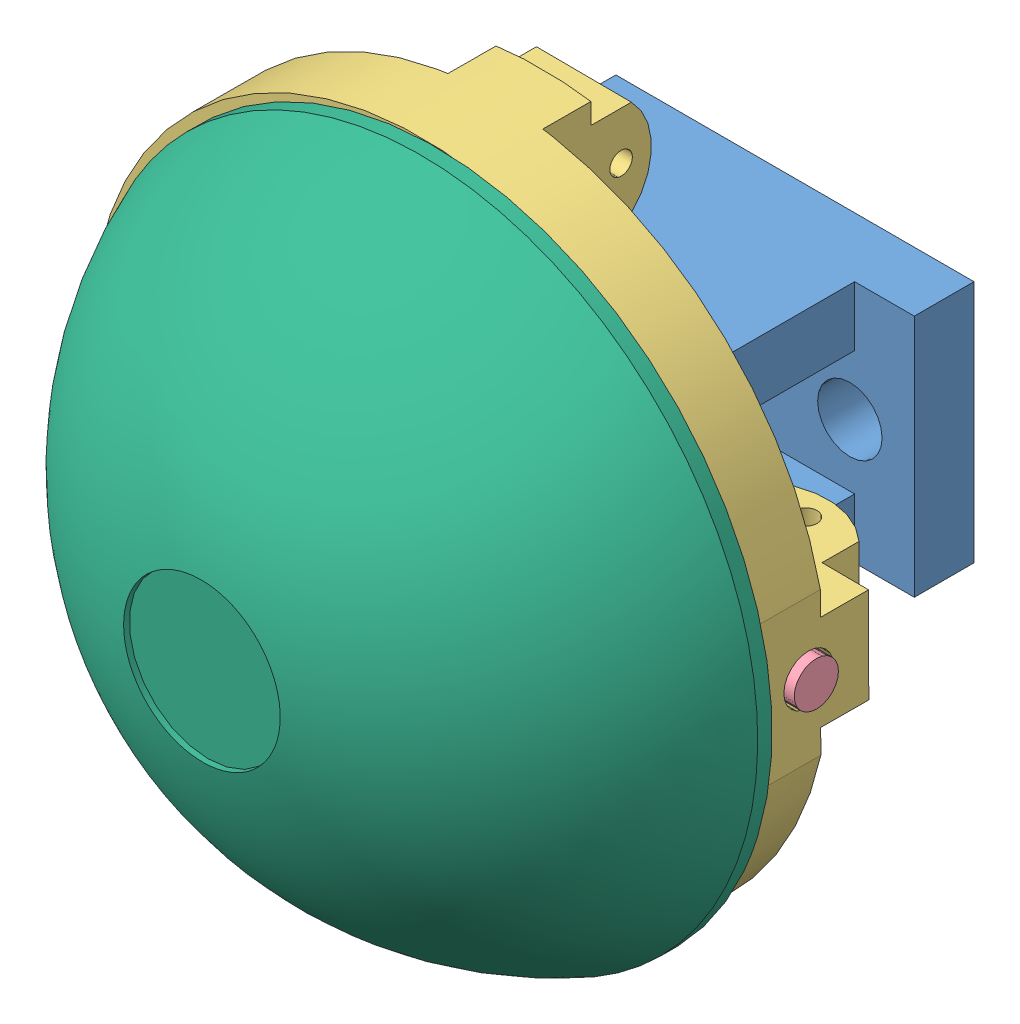
SolidWorks assembly AssemblyEye, configuration Default. Lengths in mm.
Overall size (46.12 46.08 32.11).
7 component instances, 6 part files, 11 mates.
Components (placement in the parent):
- uBracket-1: uBracket [Default] at (1.0741 -3.9515 2.1178) size (19.05 12.95 22.61)
- clevis_pin-1: clevis_pin [97245A231] at (1.0741 -5.285 7.0708) x (0.999978 0 0.006595) z (0 1 0) size (9.65 9.65 18.35)
- eyeRingr4-1: eyeRingr4 [Default] at (0.8254 2.6616 3.8941) x (0.999978 0 0.006595) z (-0.006595 -0.002852 0.999974) size (34.73 35.56 9.52)
- eyeXAxisRod-1: eyeXAxisRod [Default] at (-16.9751 2.6525 6.9518) x (0.999978 0 0.006595) z (-0.001697 -0.96631 0.257374) size (35.56 2.34 2.34)
- spacer_1_4trlong-1: spacer_1_4trlong [94639A705] at (-5.2758 2.6525 7.0289) x (-0.005467 -0.55926 0.828975) z (0.999978 0 0.006595) size (4.76 4.76 6.35)
- spacer_1_4trlong-2: spacer_1_4trlong [94639A705] at (7.4239 2.6525 7.1127) x (0.006595 0 -0.999978) z (0.999978 0 0.006595) size (4.76 4.76 6.35)
- eye-1: eye [Default] at (1.5336 2.491 10.2485) x (0.936343 -0.351049 0.005174) z (-0.006595 -0.002852 0.999974) size (35.76 35.76 12.49)
Mates (geometry in assembly coordinates):
- Concentric1: concentric anti-aligned: cylinder of uBracket-1 through (1.0741 -3.9515 7.0708) axis (0 1 0) radius 3.4925; cylinder of clevis_pin-1 through (1.0741 -6.809 7.0708) axis (0 -1 0) radius 3.175
- Coincident1: coincident anti-aligned: plane of uBracket-1 through (-5.2759 9.0025 13.4208) normal (0 1 0); plane of clevis_pin-1 through (1.0741 9.0025 7.0708) normal (0 -1 0)
- Concentric2: concentric aligned: cylinder of clevis_pin-1 through (4.249 2.6525 7.0917) axis (-0.999978 0 -0.006595) radius 1.27; cylinder of eyeXAxisRod-1 through (18.5841 2.6525 7.1863) axis (-0.999978 0 -0.006595) radius 1.1684
- Concentric3: concentric aligned: cylinder of eyeXAxisRod-1 through (18.5841 2.6525 7.1863) axis (-0.999978 0 -0.006595) radius 1.1684; cylinder of spacer_1_4trlong-1 through (-2.1009 2.6525 7.0499) axis (-0.999978 0 -0.006595) radius 1.143
- Tangent1: tangent anti-aligned: cylinder of clevis_pin-1 through (1.0741 -6.809 7.0708) axis (0 -1 0) radius 3.175; plane of spacer_1_4trlong-1 through (-2.1009 2.6525 7.0499) normal (0.999978 0 0.006595)
- Concentric6: concentric aligned: cylinder of eyeXAxisRod-1 through (18.5841 2.6525 7.1863) axis (-0.999978 0 -0.006595) radius 1.1684; cylinder of spacer_1_4trlong-2 through (10.5989 2.6525 7.1336) axis (-0.999978 0 -0.006595) radius 1.143
- Tangent3: tangent anti-aligned: cylinder of clevis_pin-1 through (1.0741 -6.809 7.0708) axis (0 -1 0) radius 3.175; plane of spacer_1_4trlong-2 through (4.249 2.6525 7.0917) normal (-0.999978 0 -0.006595)
- Concentric7: concentric aligned: cylinder of eyeRingr4-1 through (26.2039 2.6525 7.2365) axis (-0.999978 0 -0.006595) radius 1.3081; cylinder of eyeXAxisRod-1 through (18.5841 2.6525 7.1863) axis (-0.999978 0 -0.006595) radius 1.1684
- Coincident2: coincident anti-aligned: plane of eyeRingr4-1 through (10.5779 5.8184 10.3176) normal (-0.999978 0 -0.006595); plane of spacer_1_4trlong-2 through (10.5989 2.6525 7.1336) normal (0.999978 0 0.006595)
- Tangent4: tangent aligned: cylinder of eyeRingr4-1 through (0.7835 2.6435 10.2439) axis (0.006595 0.002852 -0.999974) radius 17.78; plane of eyeXAxisRod-1 through (18.5841 2.6525 7.1863) normal (0.999978 0 0.006595)
- Coincident3: coincident anti-aligned: plane of eyeRingr4-1 through (0.7835 2.6435 10.2439) normal (-0.006595 -0.002852 0.999974); plane of eye-1 through (1.5336 2.491 10.2485) normal (0.006595 0.002852 -0.999974)
